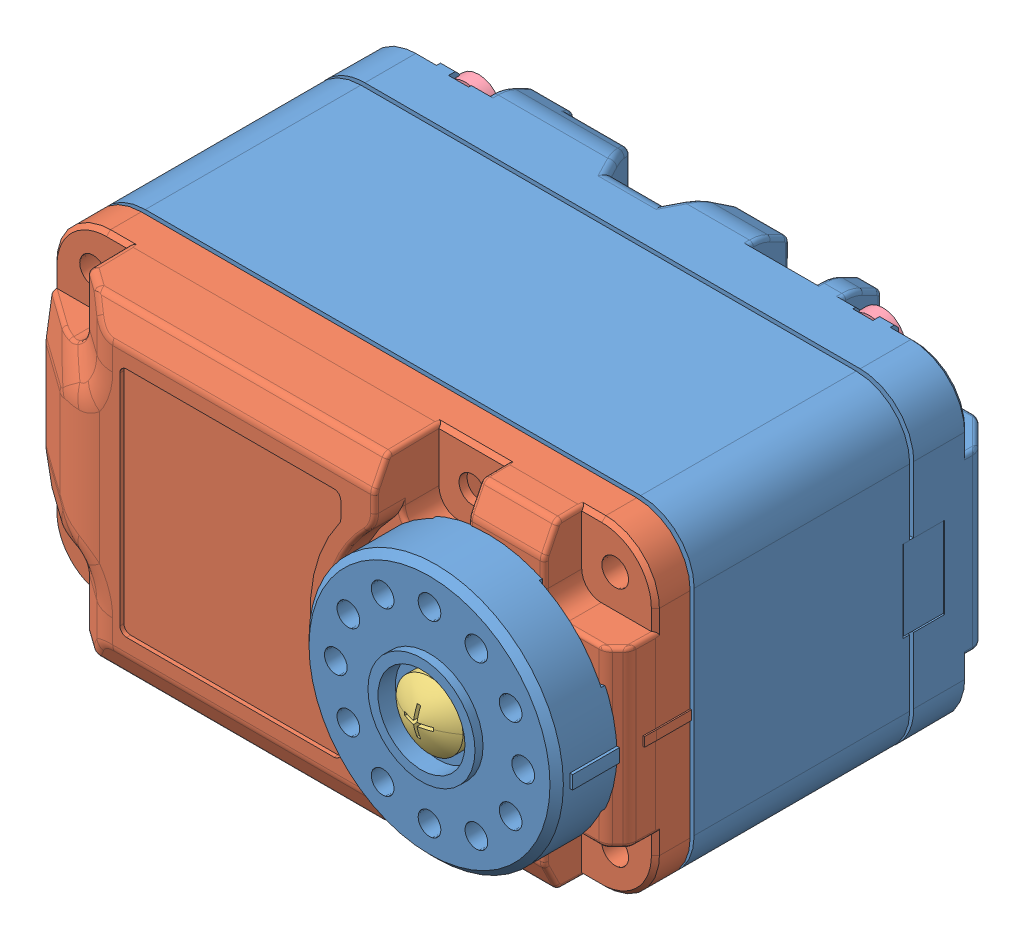
SolidWorks assembly herkulex, configuration Default. Lengths in mm.
Overall size (45.18 24.03 34.82).
7 component instances, 4 part files, 0 mates.
Components (placement in the parent):
- Document-1: Document [Default] at origin size (45.03 24.02 34.35)
- (#31287) TOP_191-1: (#31287) TOP_191 [Default] at (-8.4057 -18.0225 22.6771) x (1 0 0) z (0 1 0) size (45.18 8.06 24.03)
- (#129725) KSB1023A_M2_5X8Z-1: (#129725) KSB1023A_M2_5X8Z [Default] at (17.6225 -18.0226 34.1771) x (0 0 -1) z (0 1 0) size (9.77 5 5)
- (#112458) KSB1023A_T2X25NI-1: (#112458) KSB1023A_T2X25NI [Default] at (-10.3057 -28.0226 0.9771) x (0 0 1) z (0 1 0) size (26.48 3.4 3.4)
- (#112458) KSB1023A_T2X25NI-2: (#112458) KSB1023A_T2X25NI [Default] at (19.8943 -28.0226 0.9771) x (0 0 1) z (0 1 0) size (26.48 3.4 3.4)
- (#112458) KSB1023A_T2X25NI-3: (#112458) KSB1023A_T2X25NI [Default] at (19.8943 -8.0226 0.9771) x (0 0 1) z (0 1 0) size (26.48 3.4 3.4)
- (#112458) KSB1023A_T2X25NI-4: (#112458) KSB1023A_T2X25NI [Default] at (-10.3057 -8.0226 0.9771) x (0 0 1) z (0 1 0) size (26.48 3.4 3.4)
